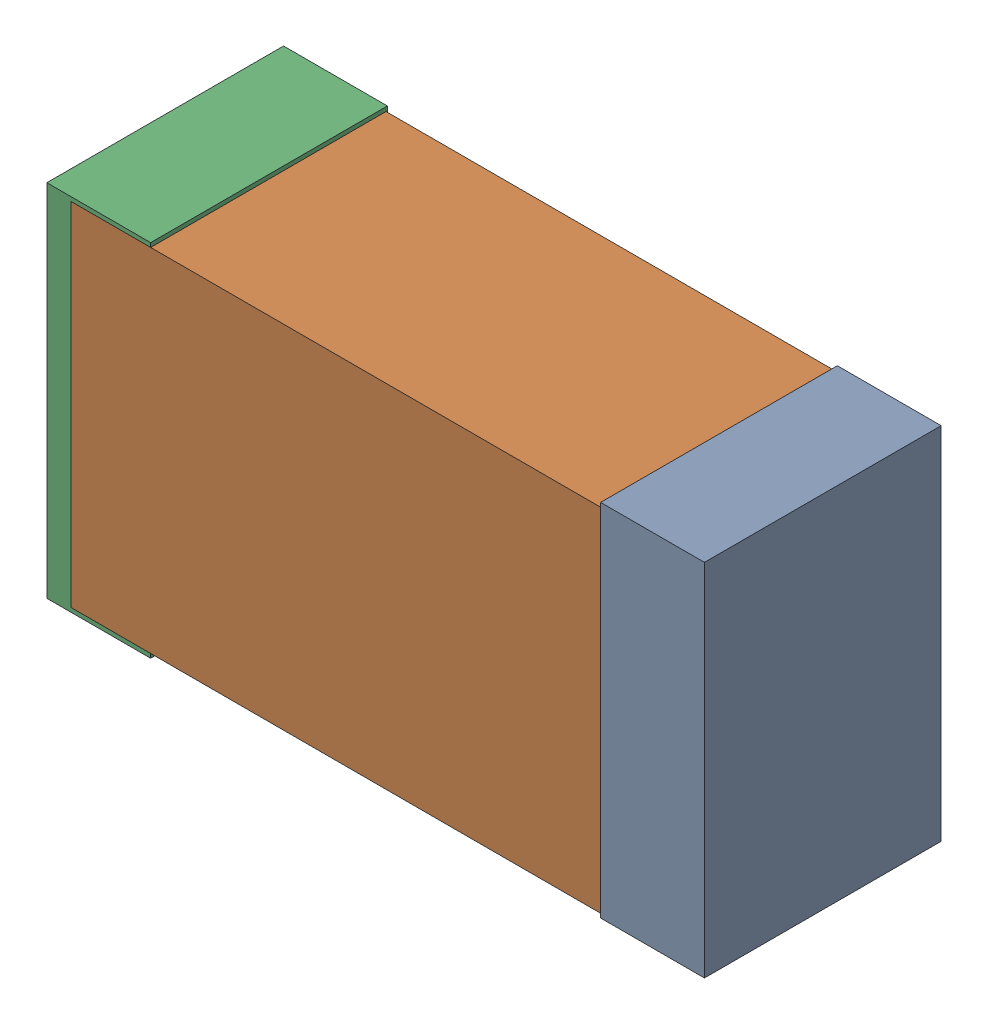
SolidWorks assembly USB67_FB3, configuration Default. Lengths in mm.
Overall size (2.38 1.3 0.85).
6 component instances, 2 part files, 0 mates.
Components (placement in the parent):
- 384311232-1: 384311232 [Default] at (152.384 83.312 -1.9574) size (0.38 1.3 0.85)
  - Extruded_8-1: Extruded_8 [Default] at origin size (0.38 1.3 0.85)
- 402662800-1: 402662800 [Default] at (151.384 83.312 -1.9524) size (2.2 1.27 0.85)
  - Extruded_30-1: Extruded_30 [Default] at origin size (2.2 1.27 0.85)
- 384311232-2: 384311232 [Default] at (150.384 83.312 -1.9574) size (0.38 1.3 0.85)
  - Extruded_8-1: Extruded_8 [Default] at origin size (0.38 1.3 0.85)
